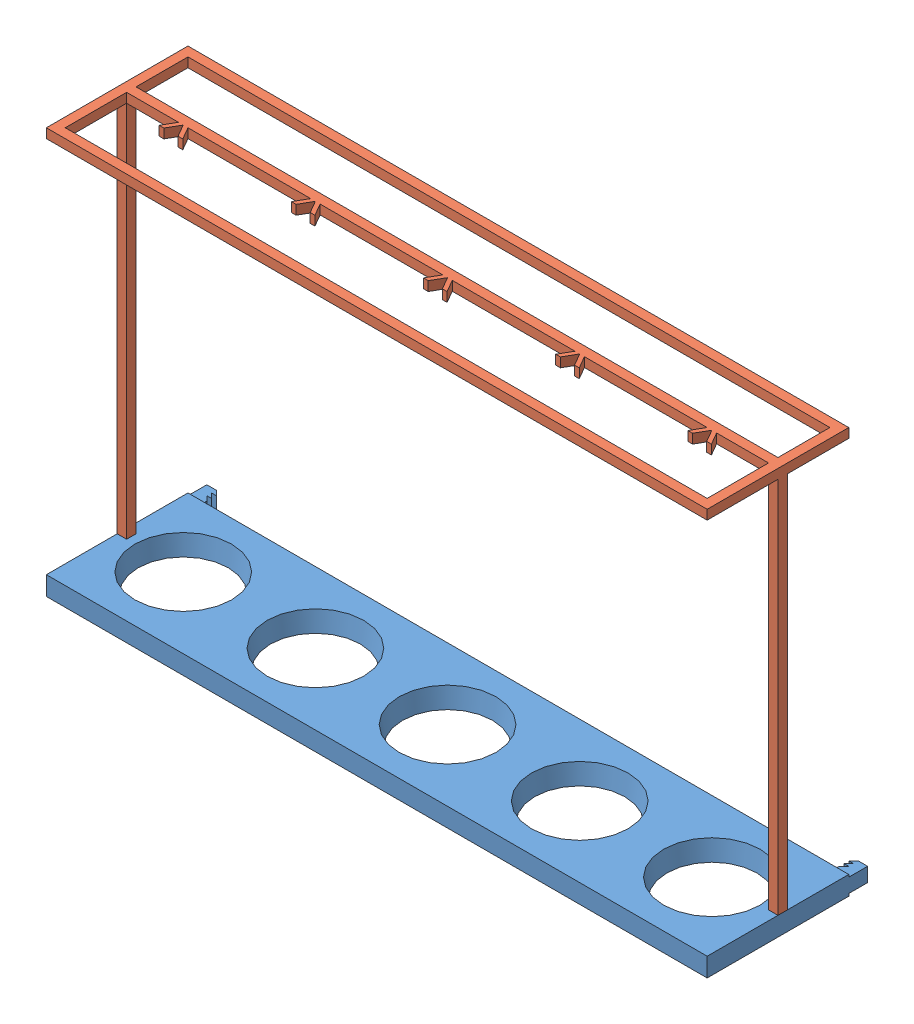
SolidWorks assembly rack new, configuration Default. Lengths in mm.
Overall size (700 487.8 170).
2 component instances, 2 part files, 3 mates.
Components (placement in the parent):
- base top-2: base top [Default] at (352.7205 384.0255 479.5472) size (700 77.8 170)
- rack top new-2: rack top new [Default] at (352.7205 804.0255 479.5472) x (-1 0 0) z (0 0 -1) size (700 410 150)
Mates (geometry in assembly coordinates):
- Coincident4: coincident aligned: plane of base top-2 through (702.7205 326.2255 404.5472) normal (1 0 0); plane of rack top new-2 through (702.7205 814.0255 404.5472) normal (1 0 0)
- Coincident5: coincident aligned: plane of base top-2 through (702.7205 326.2255 554.5472) normal (0 0 1); plane of rack top new-2 through (2.7205 814.0255 554.5472) normal (0 0 1)
- Coincident6: coincident anti-aligned: plane of base top-2 through (352.7205 404.0255 479.5472) normal (0 1 0); plane of rack top new-2 through (352.7205 404.0255 479.5472) normal (0 -1 0)
